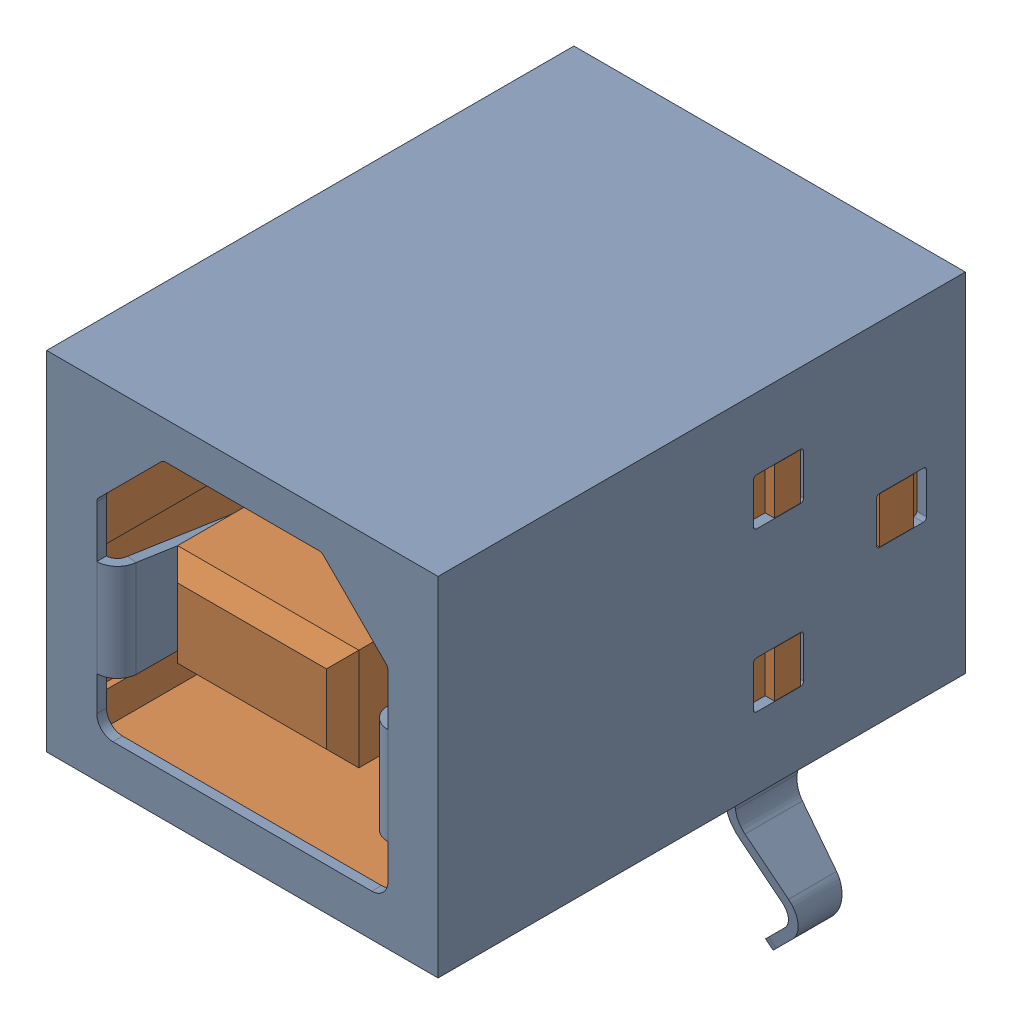
SolidWorks assembly USB Series B Receptacle, configuration Default. Lengths in mm.
Overall size (14.85 14.97 16.3).
6 component instances, 3 part files, 0 mates.
Components (placement in the parent):
- USB Series B Receptacle Metal Shell-1: USB Series B Receptacle Metal Shell [Default] x (-1 0 0) z (0 0 1) size (14.85 14.97 16.3)
- USB Series B Receptacle Housing-1: USB Series B Receptacle Housing [Default] at (0 0 -15.7) x (-1 0 0) z (0 0 1) size (12.1 10.45 15.7)
- USB Series B Receptacle Terminal-1: USB Series B Receptacle Terminal [Default] at (-0.575 1.075 -8.5) x (-1 0 0) z (0 1 0) size (1.35 12.17 0.84)
- USB Series B Receptacle Terminal-2: USB Series B Receptacle Terminal [Default] at (1.925 1.075 -8.5) x (-1 0 0) z (0 1 0) size (1.35 12.17 0.84)
- USB Series B Receptacle Terminal-3: USB Series B Receptacle Terminal [Default] at (-1.925 -1.475 -8.5) x (1 0 0) z (0 -1 0) size (1.35 12.17 0.84)
- USB Series B Receptacle Terminal-4: USB Series B Receptacle Terminal [Default] at (0.575 -1.475 -8.5) x (1 0 0) z (0 -1 0) size (1.35 12.17 0.84)
